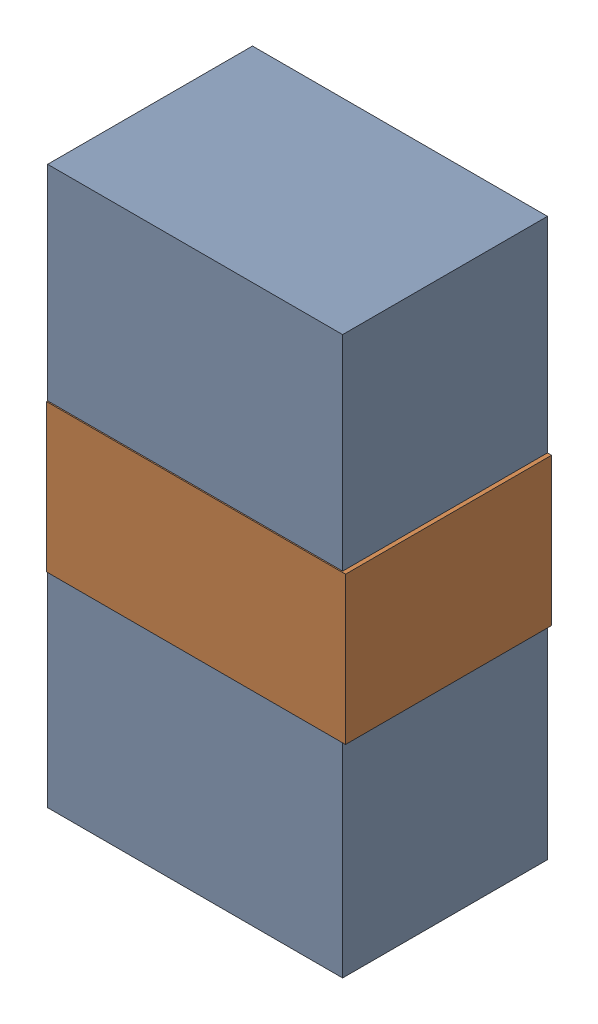
SolidWorks assembly LED2_Motor_3Kanaloa_v2.0.0_Motor, configuration Default. Lengths in mm.
Overall size (1.83 3.4 1.26).
4 component instances, 2 part files, 0 mates.
Components (placement in the parent):
- 334788016-1: 334788016 [Default] at (42.8545 90.678 0) size (1.8 3.4 1.25)
  - Extruded_12-1: Extruded_12 [Default] at origin size (1.8 3.4 1.25)
- 334787760-1: 334787760 [Default] at (42.867 90.678 0) size (1.83 0.9 1.26)
  - Extruded_13-1: Extruded_13 [Default] at origin size (1.83 0.9 1.26)
